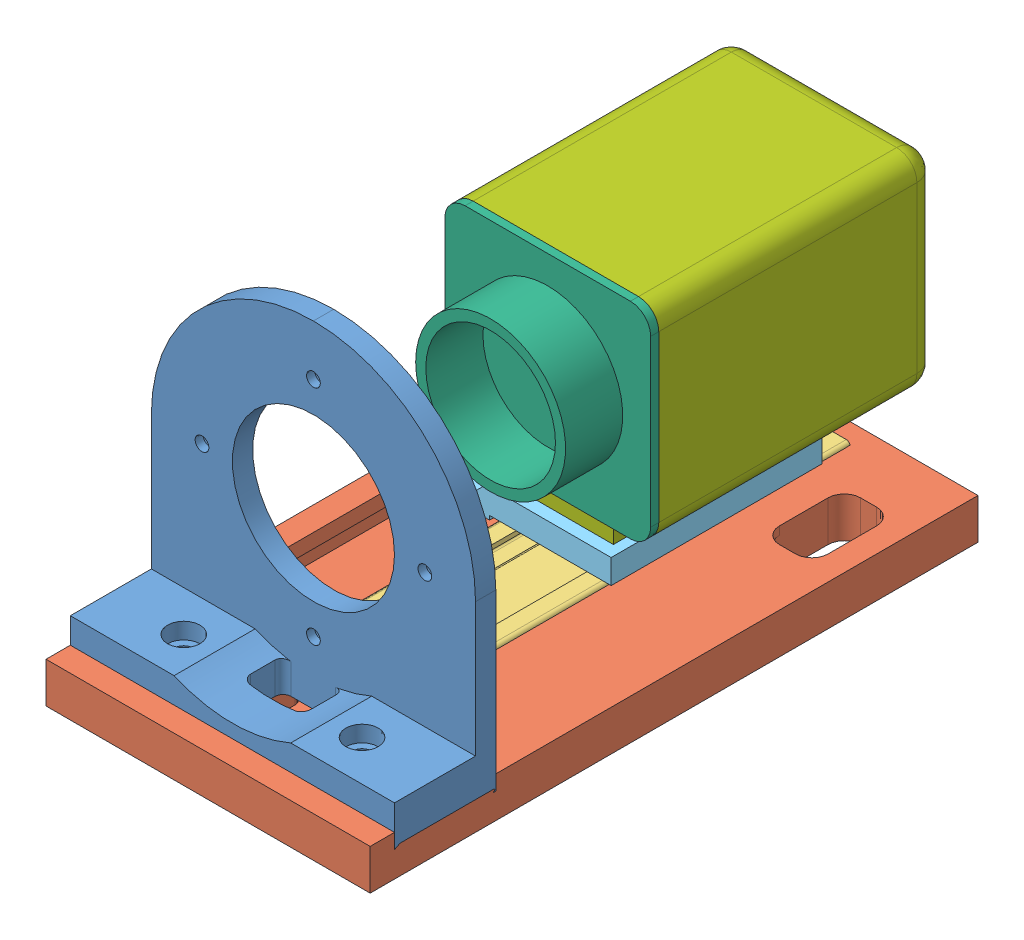
SolidWorks assembly Conjunto_visao, configuration Default. Lengths in mm.
Overall size (80 89.3 179.1).
10 component instances, 9 part files, 18 mates.
Components (placement in the parent):
- Apoio_iluminacaoLEDs-1: Apoio_iluminacaoLEDs [Default] at (0 49.3 49) size (80 83 83.14)
- Apoio_sistema_visao-1: Apoio_sistema_visao [Default] at origin size (80 10 150)
- Calha_deslizante_27mm-1: Calha_deslizante_27mm [Default] at (0 2 44) x (1 0 0) z (0 1 0) size (27 114 8.7)
- Carro_deslizante_27mm-1: Carro_deslizante_27mm [Default] at (0 1.95 -41.4686) x (1 0 0) z (0 1 0) size (23.9 40 5.35)
- Apoio_camara_27mm-1: Apoio_camara_27mm [Default] at (0 10 -61.4686) x (-1 0 0) z (0 0 -1) size (54 7 52)
- Camara-1: Camara [Default] at (-9.935 38.6559 -27.3366) size (50.8 57.8 84.8)
  - Encaixe_lente-1: Encaixe_lente [Default] at (9.935 10.7441 16.5114) size (50.8 50.8 16.1)
  - Carapaca-1: Carapaca [Default] at (9.935 10.7441 -17.8386) size (50.8 57.8 68.7)
- Hex Nut GradeC_ISO-1: Hex Nut GradeC_ISO [Hexagon Nut ISO - 4034 - M6 - C] at (-31 6.5 -35.4686) x (1 0 0) z (0 1 0) size (10 11.55 6.1)
- Socket Head Cap Screw_ISO-2: Socket Head Cap Screw_ISO [ISO 4762 M6 x 12 --- 12C] at (-31 20 -35.4686) x (0 -1 0) z (-0.997267 0 0.073888) size (18 10 10)
Mates (geometry in assembly coordinates):
- Coincident15: coincident anti-aligned: plane of Apoio_sistema_visao-1 through (-13.5 2 -70) normal (0 1 0); plane of Calha_deslizante_27mm-1 through (0 2 44) normal (0 -1 0)
- Coincident17: coincident anti-aligned: plane of Calha_deslizante_27mm-1 through (-7.95 6.1 44) normal (0 1 0); plane of Carro_deslizante_27mm-1 through (5.15 6.1 -21.4686) normal (0 -1 0)
- Width1: width: plane of Calha_deslizante_27mm-1 through (12 9.1 44) normal (-1 0 0); plane of Calha_deslizante_27mm-1 through (-12 6.6 44) normal (1 0 0); plane of Carro_deslizante_27mm-1 through (11.95 6.677 -21.4686) normal (1 0 0); plane of Carro_deslizante_27mm-1 through (-11.95 8.923 -21.4686) normal (-1 0 0)
- Concentric1: concentric anti-aligned: cylinder of Carro_deslizante_27mm-1 through (0 11.35 -31.4686) axis (0 1 0) radius 2.25; cylinder of Apoio_camara_27mm-1 through (0 11 -31.4686) axis (0 -1 0) radius 1.65
- Concentric2: concentric anti-aligned: cylinder of Carro_deslizante_27mm-1 through (0 11.35 -51.4686) axis (0 1 0) radius 2.25; cylinder of Apoio_camara_27mm-1 through (0 11 -51.4686) axis (0 -1 0) radius 1.65
- Coincident22: coincident anti-aligned: plane of Apoio_sistema_visao-1 through (-40 10 75) normal (0 1 0); plane of Apoio_camara_27mm-1 through (-15 10 -21.4686) normal (0 -1 0)
- Concentric3: concentric aligned: cylinder of Apoio_camara_27mm-1 through (0 11 -41.4686) axis (0 -1 0) radius 3.5; cylinder of Camara-1/Carapaca-1 through (0 17 -41.4686) axis (0 -1 0) radius 2.5
- Concentric4: concentric aligned: cylinder of Apoio_camara_27mm-1 through (0 11 -19.4686) axis (0 -1 0) radius 3.5; cylinder of Camara-1/Carapaca-1 through (0 17 -19.4686) axis (0 -1 0) radius 2.5
- Coincident23: coincident anti-aligned: plane of Apoio_camara_27mm-1 through (-19 17 -21.4686) normal (0 1 0); plane of Camara-1/Carapaca-1 through (-12.5 17 -46.5252) normal (0 -1 0)
- Coincident24: coincident anti-aligned: plane of Apoio_sistema_visao-1 through (-31 6.5 36) normal (0 -1 0); plane of Hex Nut GradeC_ISO-1 through (-31 6.5 -41.2421) normal (0 1 0)
- Width2: width: plane of Apoio_sistema_visao-1 through (-36.1 6.5 36) normal (1 0 0); plane of Apoio_sistema_visao-1 through (-25.9 6.5 36) normal (-1 0 0); plane of Hex Nut GradeC_ISO-1 through (-36 0.4 -38.3553) normal (-1 0 0); plane of Hex Nut GradeC_ISO-1 through (-26 0.4 -38.3553) normal (1 0 0)
- Concentric5: concentric aligned: cylinder of Apoio_camara_27mm-1 through (-31 14 -35.4686) axis (0 1 0) radius 3.1; cylinder of Hex Nut GradeC_ISO-1 through (-31 0.4 -35.4686) axis (0 1 0) radius 2.5
- Concentric7: concentric aligned: cylinder of Socket Head Cap Screw_ISO-2 through (-31 51.75 -35.4686) axis (0 1 0) radius 3; cylinder of Apoio_camara_27mm-1 through (-31 14 -35.4686) axis (0 1 0) radius 3.1
- Concentric8: concentric aligned: cylinder of Socket Head Cap Screw_ISO-2 through (-31 51.75 -35.4686) axis (0 1 0) radius 3; cylinder of Hex Nut GradeC_ISO-1 through (-31 0.4 -35.4686) axis (0 1 0) radius 2.5
- Coincident25: coincident anti-aligned: plane of Socket Head Cap Screw_ISO-2 through (-30.6306 14 -30.4822) normal (0 -1 0); plane of Apoio_camara_27mm-1 through (-39 14 -21.4686) normal (0 1 0)
- Coincident26: coincident anti-aligned: plane of Apoio_sistema_visao-1 through (-13.5 2 -70) normal (0 0 1); plane of Calha_deslizante_27mm-1 through (-10.8 3.3 -70) normal (0 0 -1)
- Coincident27: coincident: plane of Apoio_iluminacaoLEDs-1 through (40 89.3 44) normal (1 0 0); plane of Apoio_sistema_visao-1 through (40 10 -75) normal (1 0 0)
- Coincident28: coincident: plane of Apoio_iluminacaoLEDs-1 through (0 49.3 69) normal (0 0 1); line of Apoio_sistema_visao-1 through (-40 10 69) axis (1 0 0)
